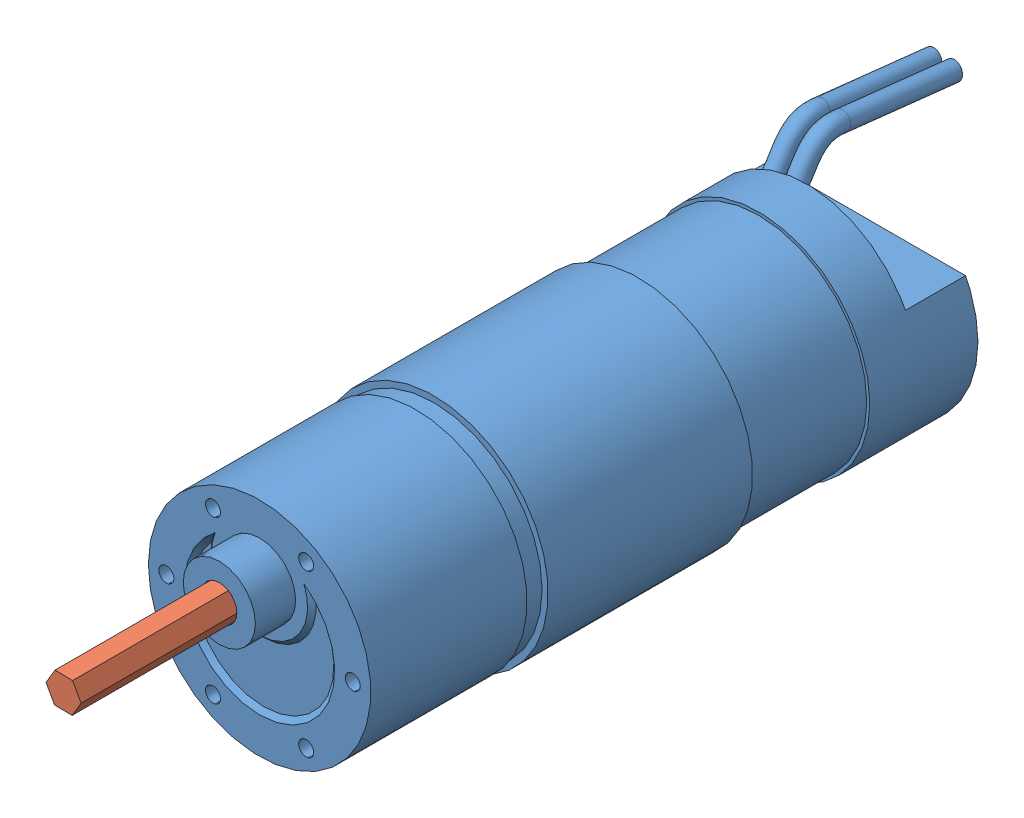
SolidWorks assembly MotorHDHexRotating, configuration Default. Lengths in mm.
Overall size (38 39.44 154.16).
2 component instances, 2 part files, 3 mates.
Components (placement in the parent):
- PART_MotorHDHex_Shell-1: PART_MotorHDHex_Shell [Default] at (52.6409 85.4657 114.2715) size (38 39.44 128.25)
- PART_MotorHDHex_RotatingHex-1: PART_MotorHDHex_RotatingHex [Default] at (52.6787 94.995 172.8795) x (0.858442 -0.512911 0) z (0.512911 0.858442 0) size (5.06 33.53 5.84)
Mates (geometry in assembly coordinates):
- Coincident1: coincident anti-aligned: plane of PART_MotorHDHex_Shell-1 through (52.6409 92.4657 139.3515) normal (0 0 1); plane of PART_MotorHDHex_RotatingHex-1 through (52.6787 94.995 139.3515) normal (0 0 -1)
- Coincident2: coincident: cylinder of PART_MotorHDHex_Shell-1 through (52.6409 92.4657 139.3515) axis (0 0 1) radius 2.921; line of PART_MotorHDHex_RotatingHex-1 through (54.1391 94.9732 139.3515) axis (0 0 1)
- Coincident4: coincident: cylinder of PART_MotorHDHex_Shell-1 through (52.6409 92.4657 139.3515) axis (0 0 1) radius 2.921; line of PART_MotorHDHex_RotatingHex-1 through (51.2184 95.0169 139.3515) axis (0 0 1)
